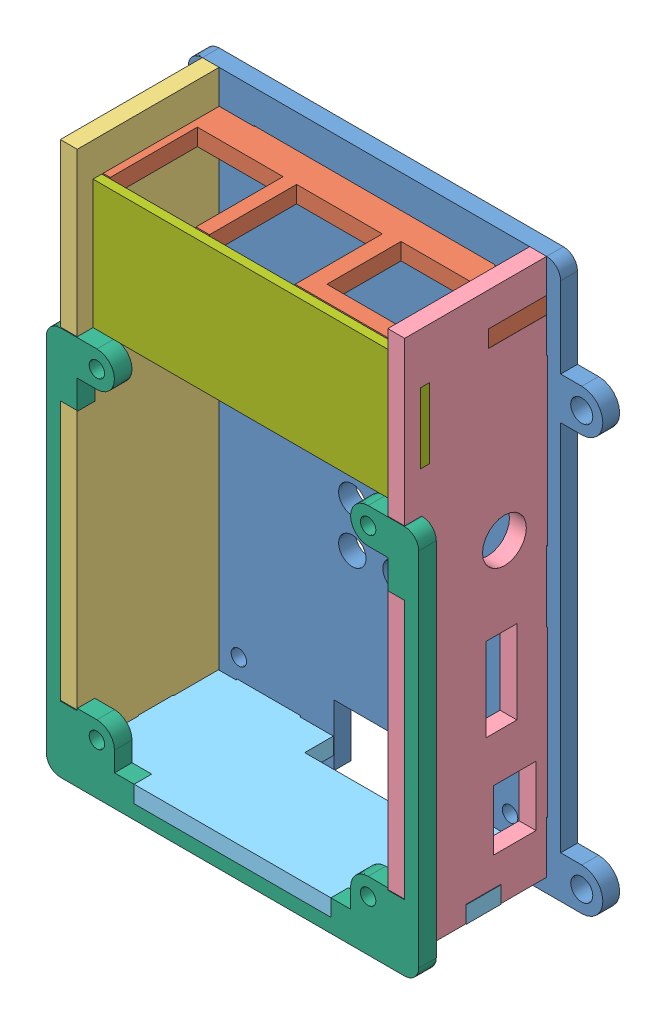
SolidWorks assembly Body, configuration Default. Lengths in mm.
Overall size (82.55 99.83 30.82).
7 component instances, 7 part files, 18 mates.
Components (placement in the parent):
- Base Plate-1: Base Plate [Default] at (-84.2145 -59.3773 31.63) size (82.55 99.69 3.05)
- front plate-1: front plate [Default] at (-19.4445 31.1787 29.508) x (-1 0 0) z (0 1 0) size (62.23 26.15 3.05)
- left plate-1: left plate [Default] at (-78.6265 -56.8323 29.508) x (0 0 1) z (-1 0 0) size (30.82 97.15 3.05)
- right plate-1: right plate [Default] at (-22.4925 -56.8577 60.332) x (0 0 -1) z (1 0 0) size (30.82 97.18 3.05)
- back plate-1: back plate [Default] at (-81.6745 -53.9163 29.635) x (1 0 0) z (0 -1 0) size (62.23 30.7 3.05)
- ai_enc_rpib+_top_panel-1: ai_enc_rpib+_top_panel [Default] at (-22.4925 -53.9163 57.157) size (67.31 70.36 3.17)
- Hood Plate-1: Hood Plate [Default] at (-78.6265 -56.8323 55.887) size (62.23 23.27 1.59)
Mates (geometry in assembly coordinates):
- Coincident1: coincident anti-aligned: plane of Base Plate-1 through (-72.2915 34.3487 34.678) normal (1 0 0); plane of front plate-1 through (-72.2915 34.2267 31.008) normal (-1 0 0)
- Coincident2: coincident anti-aligned: plane of Base Plate-1 through (-72.2915 31.1787 34.678) normal (0 1 0); plane of front plate-1 through (-70.7915 31.1787 31.008) normal (0 -1 0)
- Coincident3: coincident anti-aligned: plane of Base Plate-1 through (-81.6745 -56.8373 34.678) normal (0 0 1); plane of front plate-1 through (-19.4445 34.2267 34.678) normal (0 0 -1)
- Coincident4: coincident anti-aligned: plane of front plate-1 through (-70.7915 34.2267 31.008) normal (0 1 0); plane of left plate-1 through (-81.6745 34.2267 45.1428) normal (0 -1 0)
- Coincident5: coincident anti-aligned: plane of front plate-1 through (-78.6265 34.2267 45.1428) normal (-1 0 0); plane of left plate-1 through (-78.6265 -19.0158 31.008) normal (1 0 0)
- Coincident6: coincident anti-aligned: plane of front plate-1 through (-81.6745 34.2267 45.1428) normal (0 0 1); plane of left plate-1 through (-81.6745 34.2267 45.1428) normal (0 0 -1)
- Coincident7: coincident anti-aligned: plane of Base Plate-1 through (-81.6745 -56.8373 34.678) normal (0 0 1); plane of right plate-1 through (-19.4445 -4.9882 34.678) normal (0 0 -1)
- Coincident8: coincident aligned: line of front plate-1 through (-19.4445 34.2267 45.1428) axis (0 0 -1); line of right plate-1 through (-19.4445 34.2267 45.1428) axis (0 0 -1)
- Coincident12: coincident aligned: plane of front plate-1 through (-19.4445 34.2267 45.1428) normal (1 0 0); plane of right plate-1 through (-19.4445 -3.4882 31.008) normal (1 0 0)
- Coincident13: coincident anti-aligned: plane of Base Plate-1 through (-25.6575 -56.9643 34.678) normal (-1 0 0); plane of back plate-1 through (-25.6575 -56.9643 29.635) normal (1 0 0)
- Coincident14: coincident anti-aligned: plane of Base Plate-1 through (-37.2295 -56.9643 34.678) normal (0 1 0); plane of back plate-1 through (-81.6745 -56.9643 29.635) normal (0 -1 0)
- Coincident15: coincident anti-aligned: plane of right plate-1 through (-19.4445 -56.8577 42.933) normal (0 0 1); plane of back plate-1 through (-81.6745 -56.9643 42.933) normal (0 0 -1)
- Coincident16: coincident anti-aligned: line of right plate-1 through (-19.4445 -0.5967 60.332) axis (0 -1 0); line of ai_enc_rpib+_top_panel-1 through (-19.4445 -47.5663 60.332) axis (0 1 0)
- Coincident17: coincident aligned: line of back plate-1 through (-32.7795 -56.9643 60.332) axis (-1 0 0); line of ai_enc_rpib+_top_panel-1 through (-32.7795 -56.9643 60.332) axis (-1 0 0)
- InPlace1: in place: plane of left plate-1 through (-81.6745 31.1787 55.887) normal (0 0 1); plane of ? through (0 0 55.887) normal (0 0 1); moOrthogonalPlaneRef_w of left plate-1 through (-81.6745 31.1787 55.887) normal (0 0 1); plane of ? through (0 0 55.887) normal (0 1 0); plane of left plate-1 through (-81.6745 31.1787 55.887) normal (0 0 1); plane of ? through (0 0 55.887) normal (1 0 0); plane of left plate-1 through (-81.6745 31.1787 55.887) normal (0 0 1); unknown of Hood Plate-1
- Coincident18: coincident aligned: plane of left plate-1; plane of Hood Plate-1
- Coincident19: coincident aligned: moOrthogonalPlaneRef_w of left plate-1 through (-78.6265 -56.8323 55.887) normal (0 1 0); plane of Hood Plate-1 through (-78.6265 -56.8323 55.887) normal (0 1 0)
- Coincident20: coincident anti-aligned: moOrthogonalPlaneRef_w of left plate-1 through (-78.6265 -56.8323 55.887) normal (-1 0 0); plane of Hood Plate-1 through (-78.6265 -56.8323 55.887) normal (1 0 0)
